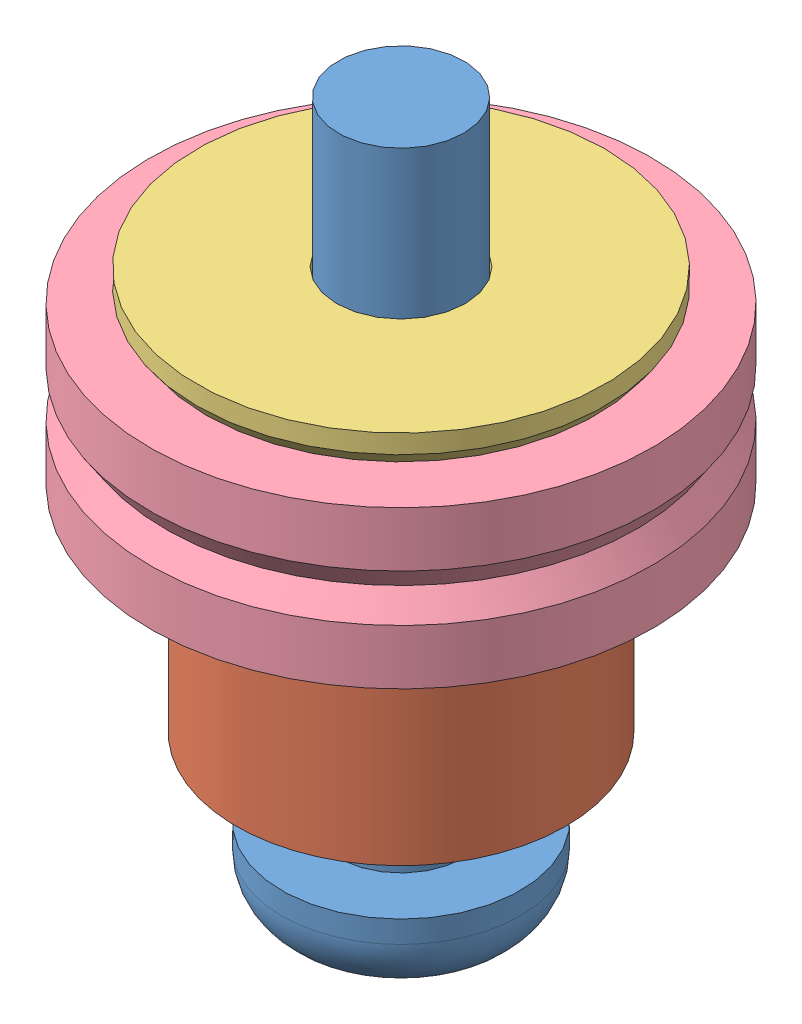
SolidWorks assembly M4 PULLEY ASSEMBLY, configuration Short. Lengths in mm.
Overall size (17.92 22.5 17.92).
4 component instances, 4 part files, 7 mates.
Components (placement in the parent):
- M4 Screw-1: M4 Screw [M4X20mm] at (0 -9.3219 0) x (0.131421 0 0.991327) z (0.991327 0 -0.131421) size (7.6 22.5 7.6)
- PULLEY SPACER 1-1: PULLEY SPACER 1 [Short] x (0.779994 0 -0.625787) z (0 -1 0) size (10.5 10.5 6.82)
- M4 V-groove pulley-1: M4 V-groove pulley [Default] at origin size (13 6 13) (hidden)
- V625ZZ-1: V625ZZ [Default] x (0 1 0) z (0.991735 0 -0.128303) size (5 16 16)
Mates (geometry in assembly coordinates):
- Coincident1: coordinate: point of M4 V-groove pulley-1
- Concentric2: concentric anti-aligned: cylinder of PULLEY SPACER 1-1 through (0 0 0) axis (0 -1 0) radius 5.25; cylinder of M4 V-groove pulley-1 through (0 -0.001 0) axis (0 1 0) radius 2.05
- Coincident3: coincident anti-aligned: plane of PULLEY SPACER 1-1 through (4.095 0 -3.2854) normal (0 1 0); plane of M4 V-groove pulley-1 through (6.5 0 0) normal (0 -1 0)
- Distance1: distance = 2.4994 mm anti-aligned: plane of PULLEY SPACER 1-1 through (0 -6.8225 0) normal (0 -1 0); plane of M4 Screw-1 through (0.2628 -9.3219 1.9827) normal (0 1 0)
- Concentric3: concentric aligned: cylinder of M4 Screw-1 through (0 10.6781 0) axis (0 1 0) radius 2; cylinder of M4 V-groove pulley-1 through (0 -0.001 0) axis (0 1 0) radius 2.05
- Concentric4: concentric anti-aligned: cylinder of M4 Screw-1 through (0 10.6781 0) axis (0 1 0) radius 2; cylinder of V625ZZ-1 through (0 5 0) axis (0 -1 0) radius 2.5
- Coincident4: coincident anti-aligned: plane of PULLEY SPACER 1-1 through (4.095 0 -3.2854) normal (0 1 0); plane of V625ZZ-1 through (0 0 0) normal (0 -1 0)
